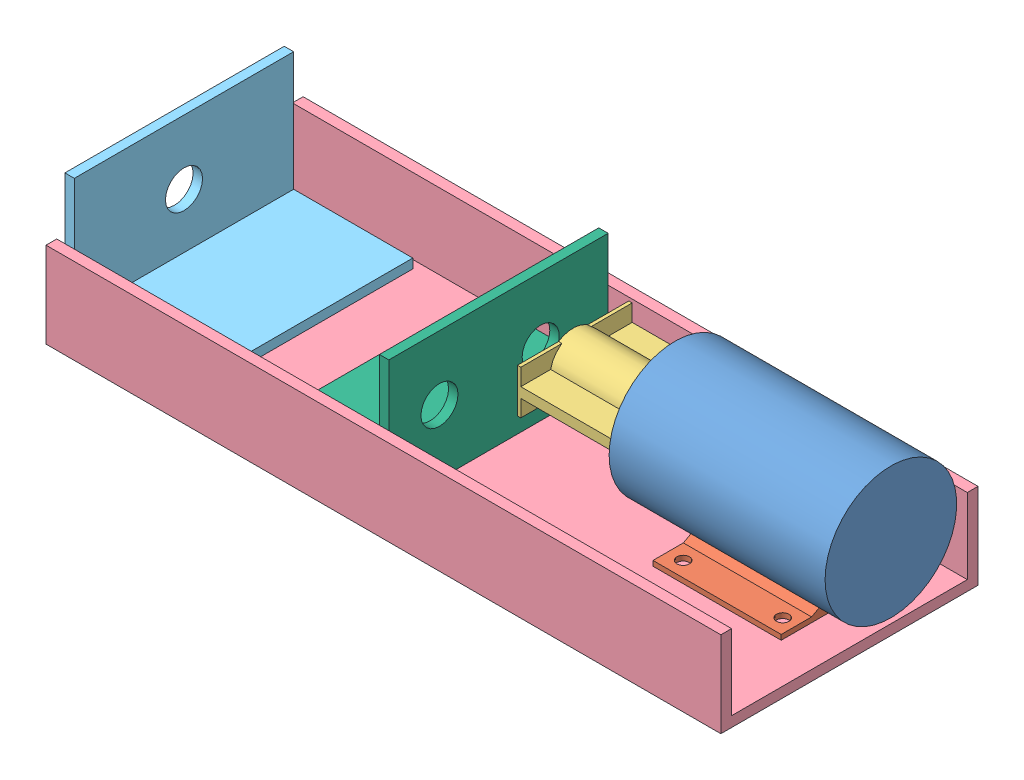
SolidWorks assembly Assem1, configuration Default. Lengths in mm.
Overall size (200 59.73 76.2).
9 component instances, 9 part files, 13 mates.
Components (placement in the parent):
- Solenoid Body-1: Solenoid Body [Default] at (-5.5994 38.7601 44.1579) size (64 39 39)
- Solenoid Plate-1: Solenoid Plate [Default] at (46.4006 38.7601 44.1579) x (0 -0.829309 0.558791) z (-1 0 0) size (24.43 35.25 38)
- Part2^Assem1-1: Part2^Assem1 [Default] at origin (virtual)
- Solenoid Rod-1: Solenoid Rod [Default] at (-35.7685 38.7601 44.1579) x (0 0 -1) z (1 0 0) size (33 15.6 82.5)
- Part4^Assem1-1: Part4^Assem1 [Default] at origin (virtual)
- Solenoid Housing-1: Solenoid Housing [Default] at (-141.5994 17.7601 70.2616) size (200 25.4 76.2)
- Part6^Assem1-1: Part6^Assem1 [Default] at origin (virtual)
- Solenoid Front 90'-3: Solenoid Front 90' [Default] at (-138.8054 20.5541 23.9386) x (0 0 1) z (-1 0 0) size (65 38.1 38.1)
- Solenoid Back 90'-2: Solenoid Back 90' [Default] at (-48.3934 20.5541 88.9386) x (0 0 -1) z (1 0 0) size (65 38.1 38.1)
Mates (geometry in assembly coordinates):
- Concentric1: concentric: cylinder of Solenoid Body-1 through (58.4006 38.7601 44.1579) axis (-1 0 0) radius 19.5; cylinder of Solenoid Plate-1 through (8.4006 38.7601 44.1579) axis (1 0 0) radius 19.5
- Distance1: distance = 12 mm: plane of Solenoid Body-1 through (58.4006 38.7601 44.1579) normal (1 0 0); plane of Solenoid Plate-1 through (46.4006 38.7601 44.1579) normal (1 0 0)
- Concentric2: concentric: cylinder of Solenoid Body-1 through (44.4006 38.7601 44.1579) axis (-1 0 0) radius 8; cylinder of Solenoid Rod-1 through (46.7315 38.7601 44.1579) axis (-1 0 0) radius 7.8
- Parallel1: parallel: plane of Solenoid Plate-1 through (8.4006 17.7601 64.6605) normal (0 -1 0); plane of Solenoid Rod-1 through (-34.7685 32.2601 27.6579) normal (0 -1 0)
- Coincident2: coincident: plane of Solenoid Plate-1 through (8.4006 17.7601 64.6605) normal (0 -1 0); plane of Solenoid Housing-1 through (58.4006 17.7601 21.5136) normal (0 1 0)
- Coincident3: coincident: plane of Solenoid Body-1 through (58.4006 38.7601 44.1579) normal (1 0 0); plane of Solenoid Housing-1 through (58.4006 17.7601 70.2616) normal (1 0 0)
- Parallel2: parallel: plane of Solenoid Plate-1 through (8.4006 19.2601 23.1605) normal (0 1 0); plane of assembly through (0 0 0) normal (0 1 0)
- Coincident14: coincident: plane of Solenoid Housing-1 through (58.4006 17.7601 21.5136) normal (0 1 0); plane of Solenoid Front 90'-3 through (-103.4994 17.7601 88.9386) normal (0 -1 0)
- Coincident15: coincident: plane of Solenoid Housing-1 through (-141.5994 17.7601 70.2616) normal (-1 0 0); plane of Solenoid Front 90'-3 through (-141.5994 17.7601 88.9386) normal (-1 0 0)
- Distance5: distance = 2.425 mm: plane of Solenoid Front 90'-3 through (-138.8054 20.5541 23.9386) normal (0 0 -1); plane of Solenoid Housing-1 through (58.4006 40.1121 21.5136) normal (0 0 1)
- Coincident17: coincident: plane of Solenoid Housing-1 through (58.4006 17.7601 21.5136) normal (0 1 0); plane of Solenoid Back 90'-2 through (-83.6994 17.7601 23.9386) normal (0 -1 0)
- Distance6: distance = 2.425 mm: plane of Solenoid Back 90'-2 through (-48.3934 20.5541 23.9386) normal (0 0 -1); plane of Solenoid Housing-1 through (58.4006 40.1121 21.5136) normal (0 0 1)
- Distance8: distance = 19.8 mm: plane of Solenoid Front 90'-3 through (-103.4994 20.5541 88.9386) normal (1 0 0); plane of Solenoid Back 90'-2 through (-83.6994 20.5541 23.9386) normal (-1 0 0)
